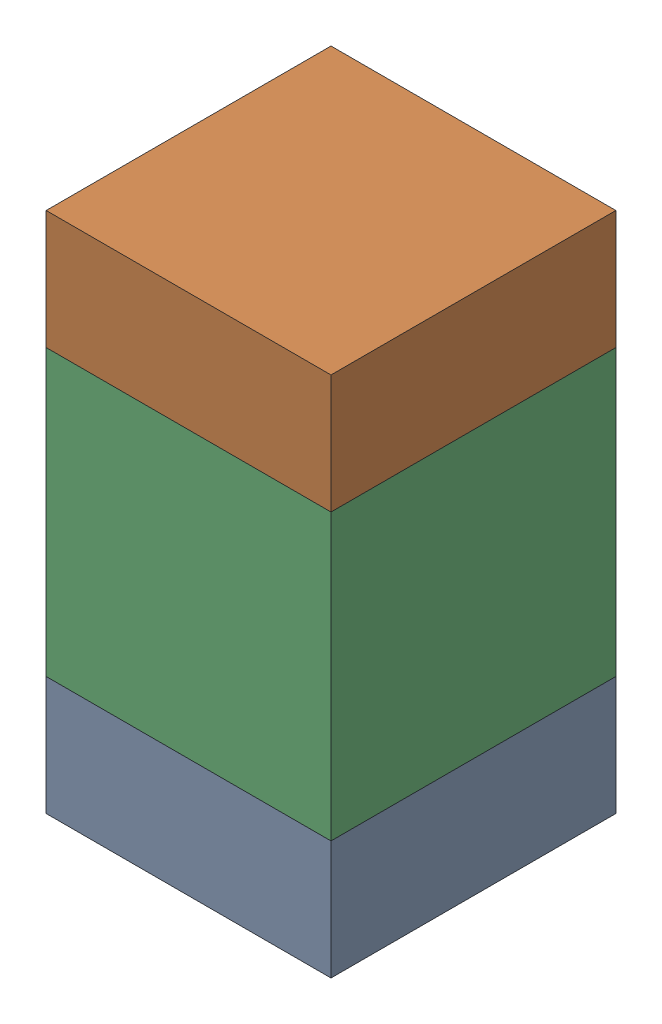
SolidWorks assembly C101_2PCB, configuration Default. Lengths in mm.
Overall size (0.6 1.1 0.6).
6 component instances, 2 part files, 0 mates.
Components (placement in the parent):
- 854785296-1: 854785296 [Default] at (108.9 99.275 0) size (0.6 0.25 0.6)
  - Extruded_10-1: Extruded_10 [Default] at origin size (0.6 0.25 0.6)
- 854785296-2: 854785296 [Default] at (108.9 100.125 0) size (0.6 0.25 0.6)
  - Extruded_10-1: Extruded_10 [Default] at origin size (0.6 0.25 0.6)
- 761606048-1: 761606048 [Default] at (108.9 99.7 0) size (0.6 0.6 0.6)
  - Extruded_9-1: Extruded_9 [Default] at origin size (0.6 0.6 0.6)
